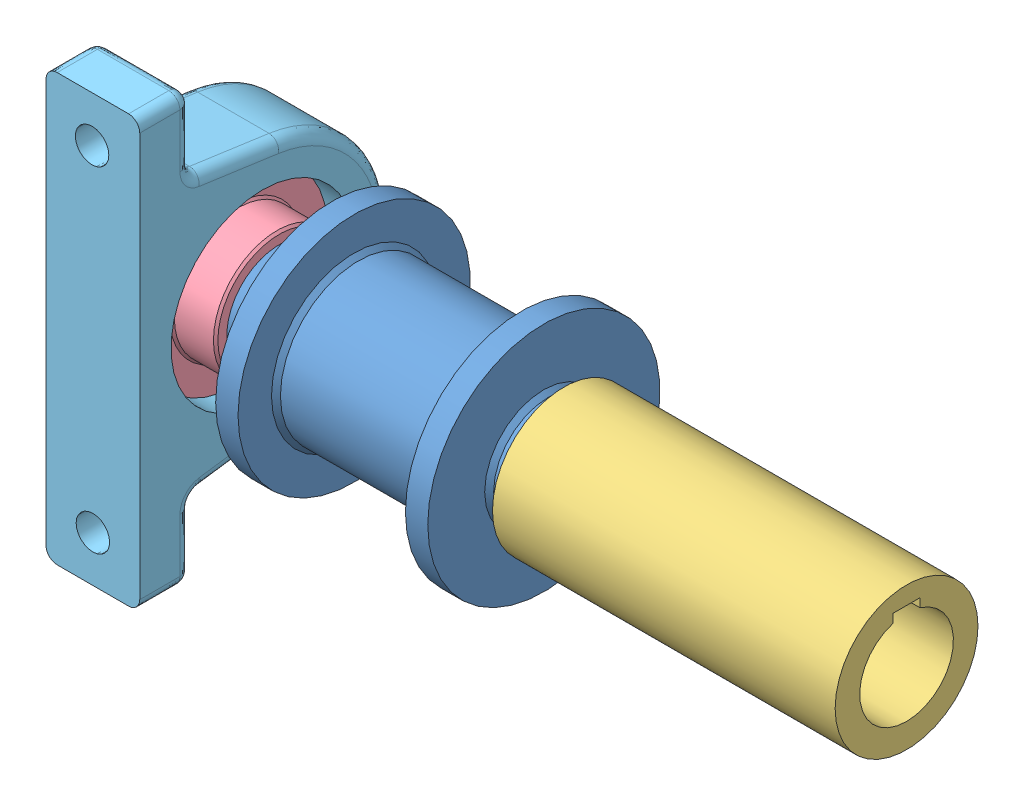
SolidWorks assembly sheave, configuration Default. Lengths in mm.
Overall size (330.5 191 112).
5 component instances, 5 part files, 14 mates.
Components (placement in the parent):
- Winge_shaft-1: Winge_shaft [Default] at origin size (234 104 104)
- 010001_winge_feather_key-1: 010001_winge_feather_key [Default] at (205 24 0) x (1 0 0) z (0 -1 0) size (50 12 8)
- Winge_connection_sleeve-1: Winge_connection_sleeve [Default] at (327.5 0 0) x (0 0 1) z (-1 0 0) size (64 64 153.5)
- Winge_bearing_GAY45_NPP_B-1: Winge_bearing_GAY45_NPP_B [Default] at (5 0 0) size (41.5 85 85)
- Winge_bearing_case-1: Winge_bearing_case [Default] at (-3 0 55) x (0 -1 0) z (1 0 0) size (191 112 42)
Mates (geometry in assembly coordinates):
- Coincident2: coincident anti-aligned: plane of Winge_shaft-1 through (184 16 0) normal (0 1 0); plane of 010001_winge_feather_key-1 through (186 16 0) normal (0 -1 0)
- Coincident3: coincident anti-aligned: plane of Winge_shaft-1 through (204 16 6) normal (0 0 -1); plane of 010001_winge_feather_key-1 through (186 16 6) normal (0 0 1)
- Concentric1: concentric aligned: cylinder of Winge_shaft-1 through (224 16 0) axis (0 1 0) radius 6; cylinder of 010001_winge_feather_key-1 through (224 16 0) axis (0 1 0) radius 6
- Concentric2: concentric anti-aligned: cylinder of Winge_shaft-1 through (0 0 0) axis (-1 0 0) radius 21; cylinder of Winge_connection_sleeve-1 through (174 0 0) axis (1 0 0) radius 21
- Coincident5: coincident anti-aligned: plane of 010001_winge_feather_key-1 through (205 16 -6) normal (0 0 -1); plane of Winge_connection_sleeve-1 through (327.5 24 -6) normal (0 0 1)
- Coincident6: coincident anti-aligned: plane of Winge_shaft-1 through (174 24.5 0) normal (1 0 0); plane of Winge_connection_sleeve-1 through (174 0 0) normal (-1 0 0)
- Concentric3: concentric anti-aligned: cylinder of Winge_shaft-1 through (0 0 0) axis (-1 0 0) radius 22.5; cylinder of Winge_bearing_GAY45_NPP_B-1 through (48.575 0 0) axis (1 0 0) radius 22.5
- Distance1: distance = 5 mm aligned: plane of Winge_shaft-1 through (0 0 0) normal (-1 0 0); plane of Winge_bearing_GAY45_NPP_B-1 through (5 22.5 0) normal (-1 0 0)
- Concentric4: concentric anti-aligned: cylinder of Winge_bearing_GAY45_NPP_B-1 through (48.575 0 0) axis (1 0 0) radius 42.5; cylinder of Winge_bearing_case-1 through (39 0 0) axis (-1 0 0) radius 41
- Distance2: distance = 8 mm aligned: plane of Winge_bearing_case-1 through (-3 0 0) normal (-1 0 0); plane of Winge_bearing_GAY45_NPP_B-1 through (5 22.5 0) normal (-1 0 0)
- Coincident12: coincident aligned: plane of Winge_shaft-1 through (0 0 0) normal (1 0 0)
- Coincident13: coincident aligned: plane of Winge_shaft-1 through (0 0 0) normal (0 1 0)
- Coincident14: coincident aligned: plane of Winge_shaft-1 through (0 0 0) normal (0 0 1)
- Parallel1: parallel aligned: plane of Winge_bearing_case-1 through (39 0 55) normal (0 0 1)
